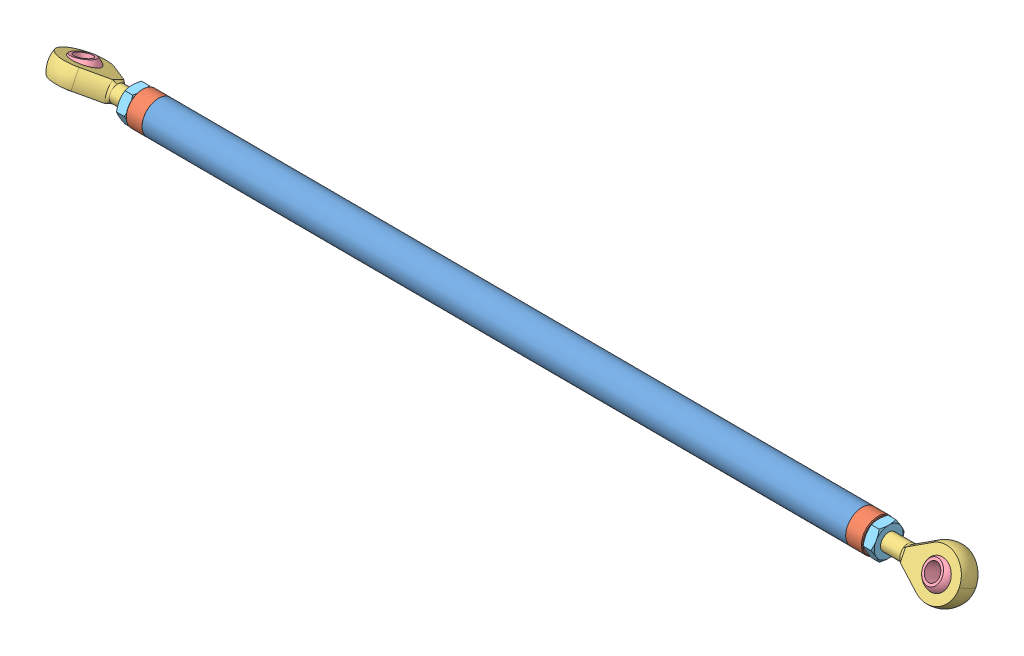
SolidWorks assembly SP-10011-AA-Rear Tie Rods, configuration Default. Lengths in mm.
Overall size (354.89 22.82 22.99).
11 component instances, 5 part files, 15 mates.
Components (placement in the parent):
- Tie Rod Tube^SP-10011-AA-Rear Tie Rods-1: Tie Rod Tube^SP-10011-AA-Rear Tie Rods [Default] at (-137.4904 0 -0.4583) x (0.999994 0 0.003334) z (-0.003334 0 0.999994) size (273.05 12.7 12.7) (virtual)
- SP-10003-AC-Threaded Insert-1: SP-10003-AC-Threaded Insert [AM-4 Rod End Thread] at (-127.9654 0 -0.4266) x (-0.001273 0.924225 0.381847) z (-0.999994 0 -0.003334) size (12.7 12.7 15.88)
- SP-10003-AC-Threaded Insert-2: SP-10003-AC-Threaded Insert [AM-4 Rod End Thread] at (126.0332 0 0.4202) x (0.003334 0 -0.999994) z (0.999994 0 0.003334) size (12.7 12.7 15.88)
- FS-MALE ROD END UNF-3A, 0.25x28-0.25D (AM-4)-1: FS-MALE ROD END UNF-3A, 0.25x28-0.25D (AM-4) [Default] at (167.64 0 0.5589) x (-0.001449 -0.900526 0.434801) z (-0.999994 0 -0.003334) size (19.32 12.47 49.44)
  - Body^FS-MALE ROD END UNF-3A, 0.25x28-0.25D (AM-4)-2: Body^FS-MALE ROD END UNF-3A, 0.25x28-0.25D (AM-4) [Default] at origin size (19.32 7.2 49.44) (virtual)
  - Ball^FS-MALE ROD END UNF-3A, 0.25x28-0.25D (AM-4)-2: Ball^FS-MALE ROD END UNF-3A, 0.25x28-0.25D (AM-4) [Default] x (0.086179 -0.13783 0.9867) z (-0.991806 -0.105624 0.071871) size (12.7 9.53 12.7) (virtual)
- FS-MALE ROD END UNF-3A, 0.25x28-0.25D (AM-4)-2: FS-MALE ROD END UNF-3A, 0.25x28-0.25D (AM-4) [Default] at (-167.64 0 -0.5589) x (-0.003002 0.434803 0.900521) z (0.999994 0 0.003334) size (19.32 12.47 49.44)
  - Body^FS-MALE ROD END UNF-3A, 0.25x28-0.25D (AM-4)-2: Body^FS-MALE ROD END UNF-3A, 0.25x28-0.25D (AM-4) [Default] at origin size (19.32 7.2 49.44) (virtual)
  - Ball^FS-MALE ROD END UNF-3A, 0.25x28-0.25D (AM-4)-2: Ball^FS-MALE ROD END UNF-3A, 0.25x28-0.25D (AM-4) [Default] x (0.086179 -0.13783 0.9867) z (-0.991806 -0.105624 0.071871) size (12.7 9.53 12.7) (virtual)
- FS-ZINC YELLOW THIN NUT G8 HX, 0.25x28-0.15625 (93839A805)-1: FS-ZINC YELLOW THIN NUT G8 HX, 0.25x28-0.15625 (93839A805) [Default] at (-145.8247 0 -0.4861) x (0.000011 0.999994 -0.003334) z (-0.003334 0.003334 0.999989) size (11.11 3.97 12.83)
- FS-ZINC YELLOW THIN NUT G8 HX, 0.25x28-0.15625 (93839A805)-2: FS-ZINC YELLOW THIN NUT G8 HX, 0.25x28-0.15625 (93839A805) [Default] at (143.8924 0 0.4797) x (0.000011 -0.999994 -0.003334) z (-0.003334 -0.003334 0.999989) size (11.11 3.97 12.83)
Mates (geometry in assembly coordinates):
- Concentric1: concentric aligned: cylinder of Tie Rod Tube^SP-10011-AA-Rear Tie Rods-1 through (-150.9607 0 -0.5033) axis (0.999994 0 0.003334) radius 4.7625; cylinder of SP-10003-AC-Threaded Insert-1 through (-137.4904 0 -0.4583) axis (0.999994 0 0.003334) radius 4.8768
- Coincident1: coincident anti-aligned: plane of Tie Rod Tube^SP-10011-AA-Rear Tie Rods-1 through (-137.4904 0 -0.4583) normal (-0.999994 0 -0.003334); circle of SP-10003-AC-Threaded Insert-1
- Concentric2: concentric anti-aligned: cylinder of Tie Rod Tube^SP-10011-AA-Rear Tie Rods-1 through (-150.9607 0 -0.5033) axis (0.999994 0 0.003334) radius 4.7625; cylinder of SP-10003-AC-Threaded Insert-2 through (135.5581 0 0.4519) axis (-0.999994 0 -0.003334) radius 4.8768
- Coincident2: coincident anti-aligned: plane of Tie Rod Tube^SP-10011-AA-Rear Tie Rods-1 through (135.5581 0 0.4519) normal (0.999994 0 0.003334); plane of SP-10003-AC-Threaded Insert-2 through (135.5581 0 0.4519) normal (-0.999994 0 -0.003334)
- Concentric3: concentric aligned: cylinder of SP-10003-AC-Threaded Insert-2 through (141.9081 0 0.4731) axis (0.999994 0 0.003334) radius 2.7051; cylinder of FS-MALE ROD END UNF-3A, 0.25x28-0.25D (AM-4)-1/Body^FS-MALE ROD END UNF-3A, 0.25x28-0.25D (AM-4)-2 through (127.9654 0 0.4266) axis (0.999994 0 0.003334) radius 3.175
- Concentric4: concentric aligned: cylinder of SP-10003-AC-Threaded Insert-1 through (-143.8403 0 -0.4795) axis (-0.999994 0 -0.003334) radius 2.7051; cylinder of FS-MALE ROD END UNF-3A, 0.25x28-0.25D (AM-4)-2/Body^FS-MALE ROD END UNF-3A, 0.25x28-0.25D (AM-4)-2 through (-127.9654 0 -0.4266) axis (-0.999994 0 -0.003334) radius 3.175
- Concentric9: concentric: cylinder of FS-MALE ROD END UNF-3A, 0.25x28-0.25D (AM-4)-2/Ball^FS-MALE ROD END UNF-3A, 0.25x28-0.25D (AM-4)-2 through (-169.4772 11.7837 -4.9245) axis (-0.144658 0.927852 -0.34375) radius 3.175
- Distance2: distance = 15.875 mm anti-aligned: plane of FS-MALE ROD END UNF-3A, 0.25x28-0.25D (AM-4)-2/Body^FS-MALE ROD END UNF-3A, 0.25x28-0.25D (AM-4)-2 through (-127.9654 0 -0.4266) normal (0.999994 0 0.003334); plane of SP-10003-AC-Threaded Insert-1 through (-143.8403 0 -0.4795) normal (-0.999994 0 -0.003334)
- Concentric7: concentric anti-aligned: cylinder of Tie Rod Tube^SP-10011-AA-Rear Tie Rods-1 through (135.5581 0 0.4519) axis (-0.999994 0 -0.003334) radius 6.35
- Concentric8: concentric: cylinder of FS-MALE ROD END UNF-3A, 0.25x28-0.25D (AM-4)-1/Ball^FS-MALE ROD END UNF-3A, 0.25x28-0.25D (AM-4)-2 through (169.5275 -6.5167 -10.177) axis (0.148622 -0.513129 -0.845346) radius 3.175
- Angle1: planar angle = 1.570796 rad anti-aligned: plane of FS-MALE ROD END UNF-3A, 0.25x28-0.25D (AM-4)-2/Body^FS-MALE ROD END UNF-3A, 0.25x28-0.25D (AM-4)-2 through (-167.6452 -3.2137 0.9928) normal (-0.001449 -0.900526 0.434801); plane of FS-MALE ROD END UNF-3A, 0.25x28-0.25D (AM-4)-1/Body^FS-MALE ROD END UNF-3A, 0.25x28-0.25D (AM-4)-2 through (167.6507 -1.5517 -2.6548) normal (0.003002 -0.434803 -0.900521)
- Concentric10: concentric anti-aligned: cylinder of FS-MALE ROD END UNF-3A, 0.25x28-0.25D (AM-4)-2/Body^FS-MALE ROD END UNF-3A, 0.25x28-0.25D (AM-4)-2 through (-127.9654 0 -0.4266) axis (-0.999994 0 -0.003334) radius 3.175; cylinder of FS-ZINC YELLOW THIN NUT G8 HX, 0.25x28-0.15625 (93839A805)-1 through (-147.8091 0 -0.4927) axis (0.999994 0 0.003334) radius 3.175
- Coincident3: coincident anti-aligned: plane of SP-10003-AC-Threaded Insert-1 through (-143.8403 0 -0.4795) normal (-0.999994 0 -0.003334); plane of FS-ZINC YELLOW THIN NUT G8 HX, 0.25x28-0.15625 (93839A805)-1 through (-143.8297 -5.5669 -3.6689) normal (0.999994 0 0.003334)
- Concentric11: concentric anti-aligned: cylinder of FS-MALE ROD END UNF-3A, 0.25x28-0.25D (AM-4)-1/Body^FS-MALE ROD END UNF-3A, 0.25x28-0.25D (AM-4)-2 through (127.9654 0 0.4266) axis (0.999994 0 0.003334) radius 3.175; cylinder of FS-ZINC YELLOW THIN NUT G8 HX, 0.25x28-0.15625 (93839A805)-2 through (145.8768 0 0.4863) axis (-0.999994 0 -0.003334) radius 3.175
- Coincident4: coincident anti-aligned: plane of SP-10003-AC-Threaded Insert-2 through (141.9081 0 0.4731) normal (0.999994 0 0.003334); plane of FS-ZINC YELLOW THIN NUT G8 HX, 0.25x28-0.15625 (93839A805)-2 through (141.9187 5.5669 -2.7163) normal (-0.999994 0 -0.003334)
